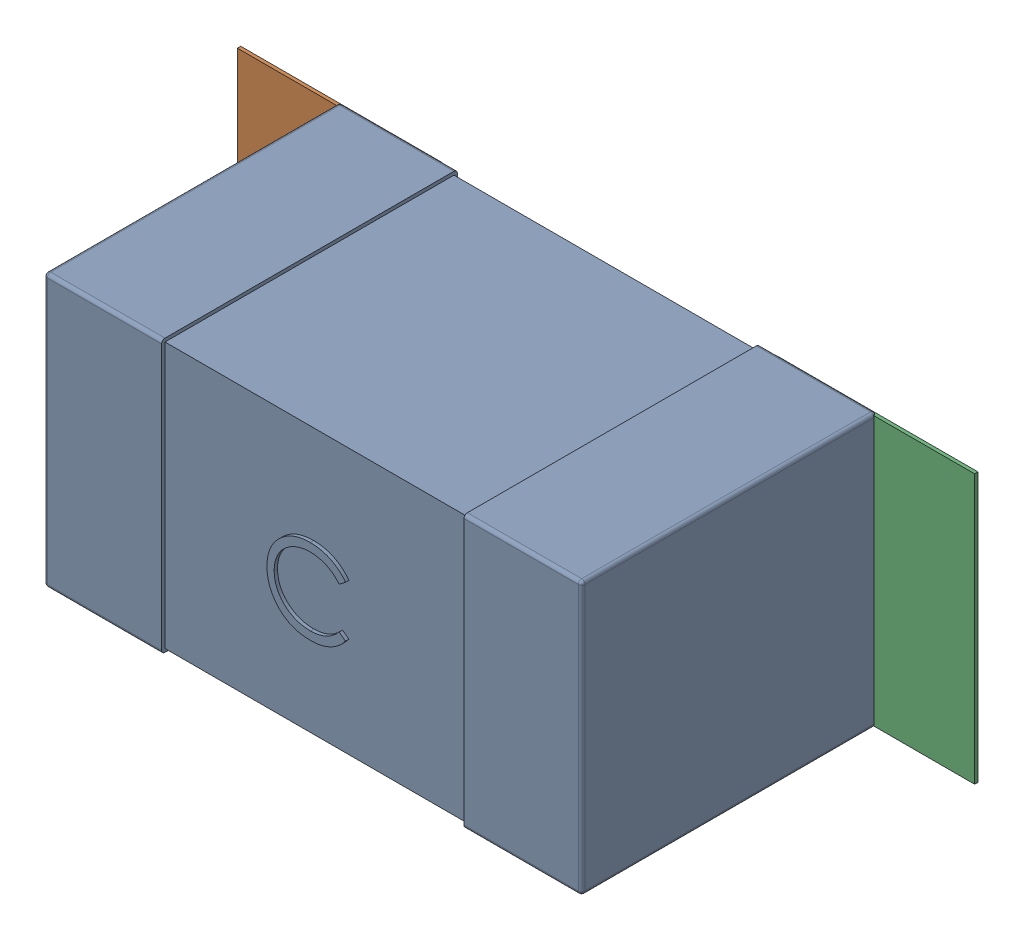
SolidWorks assembly C81, configuration Défaut. Lengths in mm.
Overall size (2.19 0.81 0.88).
5 component instances, 2 part files, 0 mates.
Components (placement in the parent):
- 0603_C-1: 0603_C [Défaut] at (34.4496 -18.9866 0) x (1 0 0) z (0 0 1) size (1.6 0.81 0.88)
- 6634915696-1: 6634915696 [Défaut] at (34.1047 -18.9866 0) size (0.6 0.8 0.01)
  - Extruded_497-1: Extruded_497 [Défaut] at origin size (0.6 0.8 0.01)
- 6634915696-2: 6634915696 [Défaut] at (35.6996 -18.9866 0) size (0.6 0.8 0.01)
  - Extruded_497-1: Extruded_497 [Défaut] at origin size (0.6 0.8 0.01)
